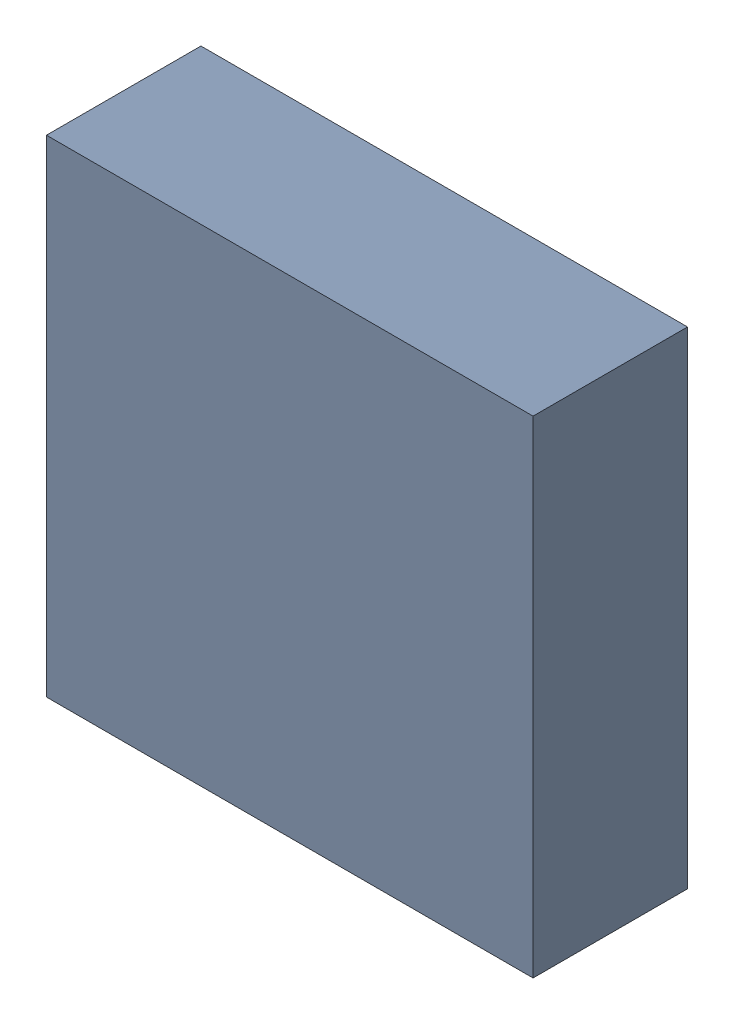
SolidWorks assembly U404PCB, configuration Default. Lengths in mm.
Overall size (3.15 3.15 1).
2 component instances, 1 part files, 0 mates.
Components (placement in the parent):
- 846484104-1: 846484104 [Default] at (121.7 87.2 -2.6638) size (3.15 3.15 1)
  - Extruded_20-1: Extruded_20 [Default] at origin size (3.15 3.15 1)
